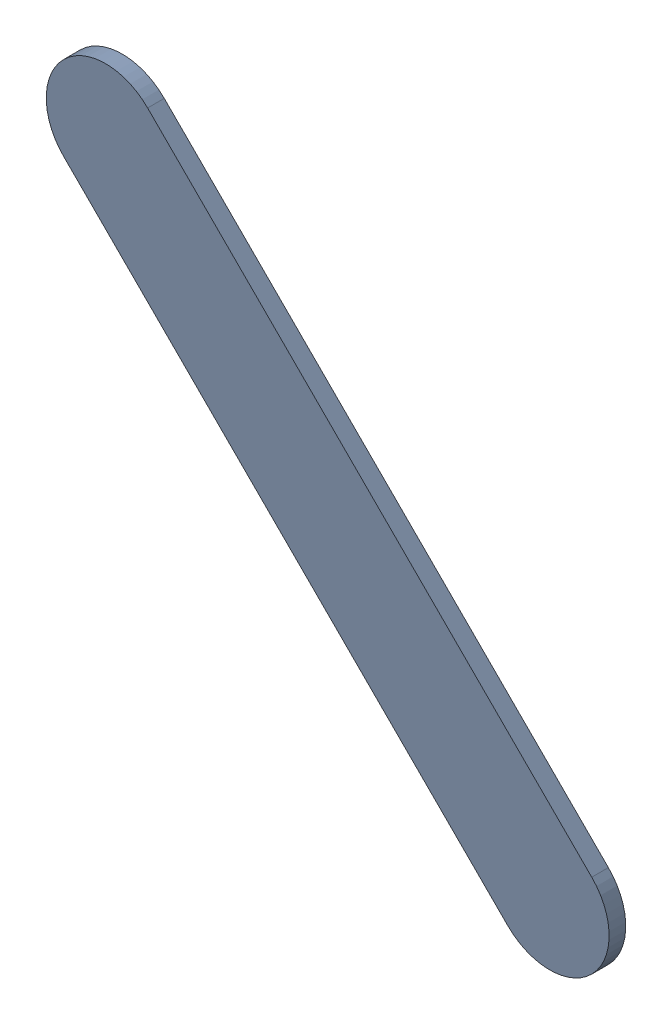
SolidWorks assembly Track (28.05mm,40.95mm)(29mm,40mm) on Top Layer, configuration Predeterminado. Lengths in mm.
Overall size (1.2 1.2 0.04).
2 component instances, 1 part files, 0 mates.
Components (placement in the parent):
- Track (28.05mm,40.95mm)(29mm,40mm) on Top Layer-1-1: Track (28.05mm,40.95mm)(29mm,40mm) on Top Layer-1 [Predeterminado] at (-68.317 -44.187 -0.0457) size (1.2 1.2 0.04)
  - Track (28.05mm,40.95mm)(29mm,40mm) on Top Layer-Part-1-1: Track (28.05mm,40.95mm)(29mm,40mm) on Top Layer-Part-1 [Predeterminado] at origin size (1.2 1.2 0.04)
